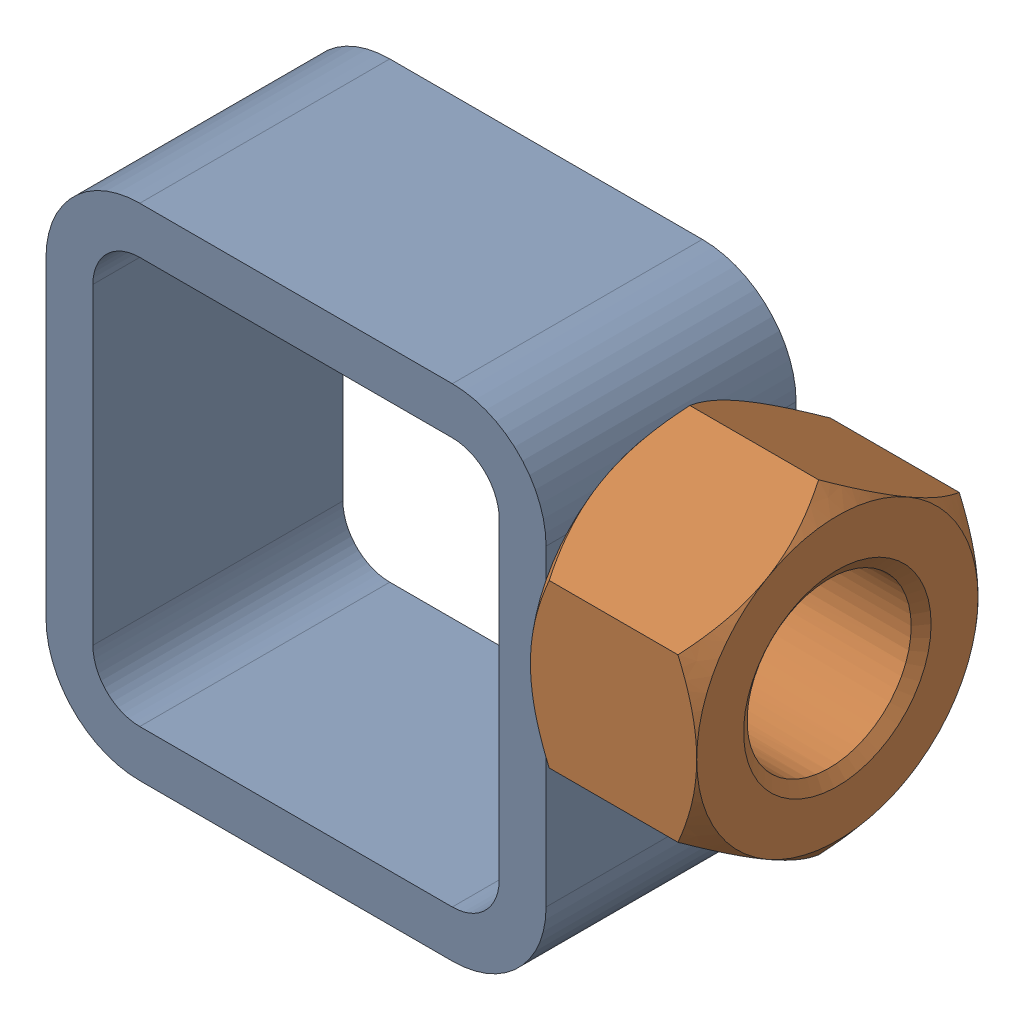
SolidWorks assembly 01-005-00-0-2, configuration Default. Lengths in mm.
Overall size (67.69 50.8 28.57).
2 component instances, 2 part files, 0 mates.
Components (placement in the parent):
- tube square_ai(PreviewCfg)-1: tube square_ai(PreviewCfg) [Default] at origin size (50.8 50.8 25.4)
- hex nut_ai(HNUT 0.7500-10-D-C)-1: hex nut_ai(HNUT 0.7500-10-D-C) [Default] at (67.691 31.75 0) x (0 0 -1) z (1 0 0) size (28.57 33 16.89)
